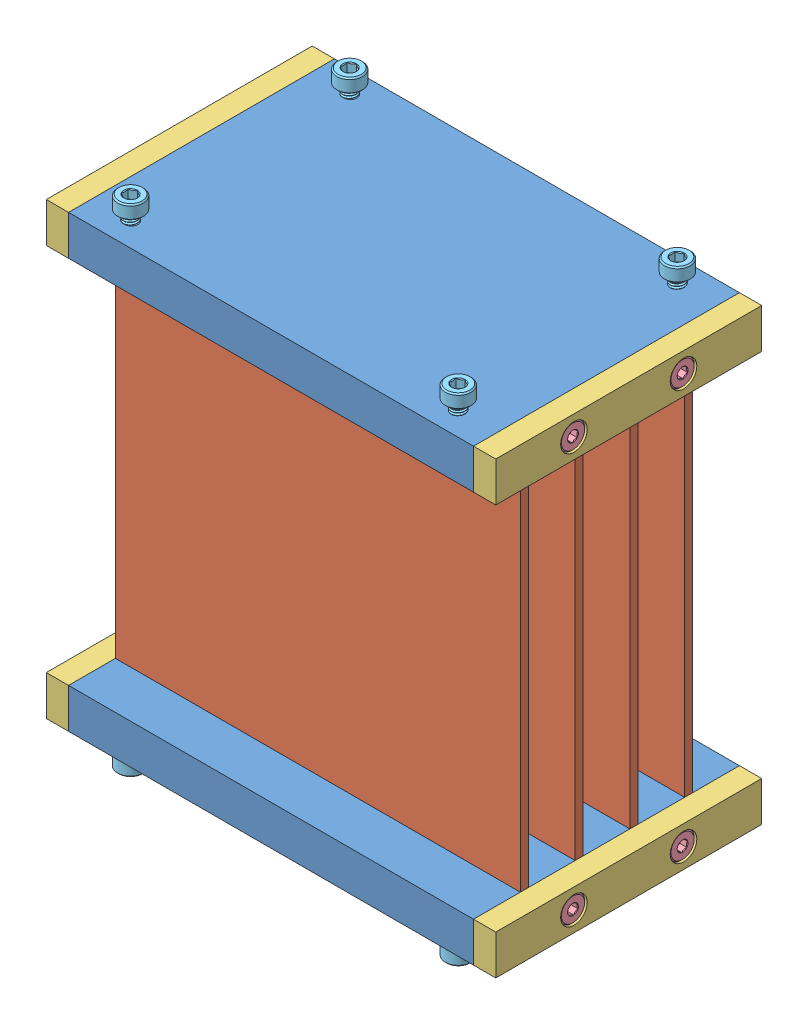
SolidWorks assembly STACK_SHELVES_ASSEMBLY, configuration Default. Lengths in mm.
Overall size (96 106.29 56.8).
26 component instances, 5 part files, 32 mates.
Components (placement in the parent):
- PCB_SHELF-1: PCB_SHELF [Default] at (-4.1696 1.9377 23.7027) x (0 1 0) z (1 0 0) size (8.5 56.8 86.5)
- FAKE_PCB-1: FAKE_PCB [Default] at (82.3304 4.4377 33.7027) x (0 1 0) z (1 0 0) size (91 1.7 86.5)
- FAKE_PCB-2: FAKE_PCB [Default] at (82.3304 4.4377 45.4027) x (0 1 0) z (1 0 0) size (91 1.7 86.5)
- FAKE_PCB-3: FAKE_PCB [Default] at (82.3304 4.4377 57.1027) x (0 1 0) z (1 0 0) size (91 1.7 86.5)
- FAKE_PCB-4: FAKE_PCB [Default] at (82.3304 4.4377 68.8027) x (0 1 0) z (1 0 0) size (91 1.7 86.5)
- PCB_SHELF-2: PCB_SHELF [Default] at (82.3304 97.9377 23.7027) x (0 -1 0) z (-1 0 0) size (8.5 56.8 86.5)
- PCB_SHELF_ENDS-1: PCB_SHELF_ENDS [Default] at (-4.1696 97.9377 80.5027) x (0 -1 0) z (-1 0 0) size (8.5 56.8 4.75)
- PCB_SHELF_ENDS-2: PCB_SHELF_ENDS [Default] at (-4.1696 10.4377 80.5027) x (0 -1 0) z (-1 0 0) size (8.5 56.8 4.75)
- PCB_SHELF_ENDS-3: PCB_SHELF_ENDS [Default] at (82.3304 89.4377 80.5027) x (0 1 0) z (1 0 0) size (8.5 56.8 4.75)
- PCB_SHELF_ENDS-4: PCB_SHELF_ENDS [Default] at (82.3304 1.9377 80.5027) x (0 1 0) z (1 0 0) size (8.5 56.8 4.75)
- M3_LP_6MM_90666A103_TYPE 316 SS LOW PROFILE SOCKET HEAD CAP SCREW-1: M3_LP_6MM_90666A103_TYPE 316 SS LOW PROFILE SOCKET HEAD CAP SCREW [90666A103] at (78.8804 6.1877 63.8027) x (0 -0.137884 0.990448) z (-1 0 0) size (5.5 5.5 8.16)
- M3_6MM_91292A111_TYPE 18-8 SS SOCKET HEAD CAP SCREW-1: M3_6MM_91292A111_TYPE 18-8 SS SOCKET HEAD CAP SCREW [91292A111] at (74.0804 93.9377 75.5027) x (0.999989 0 -0.00475) z (0 -1 0) size (5.5 5.5 9.19)
- M3_LP_6MM_90666A103_TYPE 316 SS LOW PROFILE SOCKET HEAD CAP SCREW-2: M3_LP_6MM_90666A103_TYPE 316 SS LOW PROFILE SOCKET HEAD CAP SCREW [90666A103] at (78.8804 6.1877 40.4027) x (0 -0.137884 -0.990448) z (-1 0 0) size (5.5 5.5 8.16)
- M3_LP_6MM_90666A103_TYPE 316 SS LOW PROFILE SOCKET HEAD CAP SCREW-3: M3_LP_6MM_90666A103_TYPE 316 SS LOW PROFILE SOCKET HEAD CAP SCREW [90666A103] at (78.8804 93.6877 63.8027) x (0 0.137884 0.990448) z (-1 0 0) size (5.5 5.5 8.16)
- M3_LP_6MM_90666A103_TYPE 316 SS LOW PROFILE SOCKET HEAD CAP SCREW-4: M3_LP_6MM_90666A103_TYPE 316 SS LOW PROFILE SOCKET HEAD CAP SCREW [90666A103] at (78.8804 93.6877 40.4027) x (0 0.137884 -0.990448) z (-1 0 0) size (5.5 5.5 8.16)
- M3_LP_6MM_90666A103_TYPE 316 SS LOW PROFILE SOCKET HEAD CAP SCREW-5: M3_LP_6MM_90666A103_TYPE 316 SS LOW PROFILE SOCKET HEAD CAP SCREW [90666A103] at (-0.7196 6.1877 63.8027) x (0 -0.137884 0.990448) z (1 0 0) size (5.5 5.5 8.16)
- M3_LP_6MM_90666A103_TYPE 316 SS LOW PROFILE SOCKET HEAD CAP SCREW-6: M3_LP_6MM_90666A103_TYPE 316 SS LOW PROFILE SOCKET HEAD CAP SCREW [90666A103] at (-0.7196 6.1877 40.4027) x (0 -0.137884 -0.990448) z (1 0 0) size (5.5 5.5 8.16)
- M3_LP_6MM_90666A103_TYPE 316 SS LOW PROFILE SOCKET HEAD CAP SCREW-7: M3_LP_6MM_90666A103_TYPE 316 SS LOW PROFILE SOCKET HEAD CAP SCREW [90666A103] at (-0.7196 93.6877 63.8027) x (0 0.137884 0.990448) z (1 0 0) size (5.5 5.5 8.16)
- M3_LP_6MM_90666A103_TYPE 316 SS LOW PROFILE SOCKET HEAD CAP SCREW-8: M3_LP_6MM_90666A103_TYPE 316 SS LOW PROFILE SOCKET HEAD CAP SCREW [90666A103] at (-0.7196 93.6877 40.4027) x (0 0.137884 -0.990448) z (1 0 0) size (5.5 5.5 8.16)
- M3_6MM_91292A111_TYPE 18-8 SS SOCKET HEAD CAP SCREW-2: M3_6MM_91292A111_TYPE 18-8 SS SOCKET HEAD CAP SCREW [91292A111] at (74.0804 93.9377 28.7027) x (0.999989 0 0.00475) z (0 -1 0) size (5.5 5.5 9.19)
- M3_6MM_91292A111_TYPE 18-8 SS SOCKET HEAD CAP SCREW-3: M3_6MM_91292A111_TYPE 18-8 SS SOCKET HEAD CAP SCREW [91292A111] at (4.0804 93.9377 75.5027) x (-0.999989 0 -0.00475) z (0 -1 0) size (5.5 5.5 9.19)
- M3_6MM_91292A111_TYPE 18-8 SS SOCKET HEAD CAP SCREW-4: M3_6MM_91292A111_TYPE 18-8 SS SOCKET HEAD CAP SCREW [91292A111] at (4.0804 93.9377 28.7027) x (-0.999989 0 0.00475) z (0 -1 0) size (5.5 5.5 9.19)
- M3_6MM_91292A111_TYPE 18-8 SS SOCKET HEAD CAP SCREW-5: M3_6MM_91292A111_TYPE 18-8 SS SOCKET HEAD CAP SCREW [91292A111] at (74.0804 5.9377 75.5027) x (0.999989 0 -0.00475) z (0 1 0) size (5.5 5.5 9.19)
- M3_6MM_91292A111_TYPE 18-8 SS SOCKET HEAD CAP SCREW-6: M3_6MM_91292A111_TYPE 18-8 SS SOCKET HEAD CAP SCREW [91292A111] at (74.0804 5.9377 28.7027) x (0.999989 0 0.00475) z (0 1 0) size (5.5 5.5 9.19)
- M3_6MM_91292A111_TYPE 18-8 SS SOCKET HEAD CAP SCREW-7: M3_6MM_91292A111_TYPE 18-8 SS SOCKET HEAD CAP SCREW [91292A111] at (4.0804 5.9377 75.5027) x (-0.999989 0 -0.00475) z (0 1 0) size (5.5 5.5 9.19)
- M3_6MM_91292A111_TYPE 18-8 SS SOCKET HEAD CAP SCREW-8: M3_6MM_91292A111_TYPE 18-8 SS SOCKET HEAD CAP SCREW [91292A111] at (4.0804 5.9377 28.7027) x (-0.999989 0 0.00475) z (0 1 0) size (5.5 5.5 9.19)
Mates (geometry in assembly coordinates):
- Coincident10: coincident anti-aligned: plane of PCB_SHELF-1 through (82.3304 4.4377 35.4027) normal (0 1 0); plane of FAKE_PCB-1 through (82.3304 4.4377 35.4027) normal (0 -1 0)
- Coincident11: coincident anti-aligned: plane of PCB_SHELF-1 through (82.3304 4.4377 33.7027) normal (0 0 1); plane of FAKE_PCB-1 through (82.3304 4.4377 33.7027) normal (0 0 -1)
- Coincident12: coincident aligned: plane of PCB_SHELF-1 through (82.3304 1.9377 23.7027) normal (1 0 0); plane of FAKE_PCB-1 through (82.3304 95.4377 35.4027) normal (1 0 0)
- Coincident13: coincident anti-aligned: plane of PCB_SHELF-1 through (82.3304 4.4377 47.1027) normal (0 1 0); plane of FAKE_PCB-2 through (82.3304 4.4377 47.1027) normal (0 -1 0)
- Coincident14: coincident anti-aligned: plane of PCB_SHELF-1 through (82.3304 4.4377 45.4027) normal (0 0 1); plane of FAKE_PCB-2 through (82.3304 4.4377 45.4027) normal (0 0 -1)
- Coincident15: coincident aligned: plane of PCB_SHELF-1 through (-4.1696 1.9377 23.7027) normal (-1 0 0); plane of FAKE_PCB-2 through (-4.1696 4.4377 47.1027) normal (-1 0 0)
- Coincident16: coincident anti-aligned: plane of PCB_SHELF-1 through (82.3304 4.4377 58.8027) normal (0 1 0); plane of FAKE_PCB-3 through (82.3304 4.4377 58.8027) normal (0 -1 0)
- Coincident17: coincident anti-aligned: plane of PCB_SHELF-1 through (82.3304 4.4377 57.1027) normal (0 0 1); plane of FAKE_PCB-3 through (82.3304 4.4377 57.1027) normal (0 0 -1)
- Coincident18: coincident aligned: plane of PCB_SHELF-1 through (-4.1696 1.9377 23.7027) normal (-1 0 0); plane of FAKE_PCB-3 through (-4.1696 4.4377 58.8027) normal (-1 0 0)
- Coincident19: coincident anti-aligned: plane of PCB_SHELF-1 through (82.3304 4.4377 70.5027) normal (0 1 0); plane of FAKE_PCB-4 through (82.3304 4.4377 70.5027) normal (0 -1 0)
- Coincident20: coincident anti-aligned: plane of PCB_SHELF-1 through (82.3304 4.4377 68.8027) normal (0 0 1); plane of FAKE_PCB-4 through (82.3304 4.4377 68.8027) normal (0 0 -1)
- Coincident21: coincident aligned: plane of PCB_SHELF-1 through (-4.1696 1.9377 23.7027) normal (-1 0 0); plane of FAKE_PCB-4 through (-4.1696 4.4377 70.5027) normal (-1 0 0)
- Coincident22: coincident anti-aligned: plane of FAKE_PCB-4 through (-4.1696 95.4377 70.5027) normal (0 1 0); plane of PCB_SHELF-2 through (-4.1696 95.4377 70.5027) normal (0 -1 0)
- Coincident23: coincident aligned: plane of FAKE_PCB-4 through (82.3304 95.4377 70.5027) normal (1 0 0); plane of PCB_SHELF-2 through (82.3304 97.9377 23.7027) normal (1 0 0)
- Coincident24: coincident aligned: plane of FAKE_PCB-1 through (82.3304 95.4377 35.4027) normal (1 0 0); plane of PCB_SHELF-2 through (82.3304 97.9377 23.7027) normal (1 0 0)
- Coincident25: coincident anti-aligned: plane of FAKE_PCB-1 through (82.3304 4.4377 35.4027) normal (0 0 1); plane of PCB_SHELF-2 through (-4.1696 89.4377 35.4027) normal (0 0 -1)
- Concentric1: concentric aligned: cylinder of PCB_SHELF-1 through (82.3304 6.1877 63.8027) axis (1 0 0) radius 1.25; cylinder of PCB_SHELF_ENDS-4 through (87.0804 6.1877 63.8027) axis (1 0 0) radius 1.5
- Coincident26: coincident anti-aligned: plane of PCB_SHELF-1 through (82.3304 1.9377 23.7027) normal (1 0 0); plane of PCB_SHELF_ENDS-4 through (82.3304 1.9377 80.5027) normal (-1 0 0)
- Concentric2: concentric aligned: cylinder of PCB_SHELF-1 through (82.3304 6.1877 40.4027) axis (1 0 0) radius 1.25; cylinder of PCB_SHELF_ENDS-4 through (87.0804 6.1877 40.4027) axis (1 0 0) radius 1.5
- Coincident27: coincident anti-aligned: plane of PCB_SHELF-2 through (82.3304 97.9377 23.7027) normal (1 0 0); plane of PCB_SHELF_ENDS-3 through (82.3304 89.4377 80.5027) normal (-1 0 0)
- Concentric3: concentric aligned: cylinder of PCB_SHELF-2 through (82.3304 93.6877 63.8027) axis (1 0 0) radius 1.25; cylinder of PCB_SHELF_ENDS-3 through (87.0804 93.6877 63.8027) axis (1 0 0) radius 1.5
- Concentric4: concentric aligned: cylinder of PCB_SHELF-2 through (82.3304 93.6877 40.4027) axis (1 0 0) radius 1.25; cylinder of PCB_SHELF_ENDS-3 through (87.0804 93.6877 40.4027) axis (1 0 0) radius 1.5
- Coincident28: coincident anti-aligned: plane of PCB_SHELF-1 through (-4.1696 1.9377 23.7027) normal (-1 0 0); plane of PCB_SHELF_ENDS-2 through (-4.1696 10.4377 80.5027) normal (1 0 0)
- Concentric5: concentric aligned: cylinder of PCB_SHELF-1 through (-4.1696 6.1877 63.8027) axis (-1 0 0) radius 1.25; cylinder of PCB_SHELF_ENDS-2 through (-8.9196 6.1877 63.8027) axis (-1 0 0) radius 1.5
- Concentric6: concentric aligned: cylinder of PCB_SHELF-1 through (-4.1696 6.1877 40.4027) axis (-1 0 0) radius 1.25; cylinder of PCB_SHELF_ENDS-2 through (-8.9196 6.1877 40.4027) axis (-1 0 0) radius 1.5
- Coincident29: coincident anti-aligned: plane of PCB_SHELF-2 through (-4.1696 97.9377 23.7027) normal (-1 0 0); plane of PCB_SHELF_ENDS-1 through (-4.1696 97.9377 80.5027) normal (1 0 0)
- Concentric7: concentric aligned: cylinder of PCB_SHELF-2 through (-4.1696 93.6877 63.8027) axis (-1 0 0) radius 1.25; cylinder of PCB_SHELF_ENDS-1 through (-8.9196 93.6877 63.8027) axis (-1 0 0) radius 1.5
- Concentric8: concentric aligned: cylinder of PCB_SHELF-2 through (-4.1696 93.6877 40.4027) axis (-1 0 0) radius 1.25; cylinder of PCB_SHELF_ENDS-1 through (-8.9196 93.6877 40.4027) axis (-1 0 0) radius 1.5
- Concentric9: concentric anti-aligned: circle of PCB_SHELF_ENDS-4; circle of M3_LP_6MM_90666A103_TYPE 316 SS LOW PROFILE SOCKET HEAD CAP SCREW-1
- Coincident31: coincident anti-aligned: plane of PCB_SHELF_ENDS-4 through (84.8804 6.1877 63.8027) normal (1 0 0); plane of M3_LP_6MM_90666A103_TYPE 316 SS LOW PROFILE SOCKET HEAD CAP SCREW-1 through (84.8804 6.1877 63.8027) normal (-1 0 0)
- Concentric10: concentric anti-aligned: circle of PCB_SHELF-2; circle of M3_6MM_91292A111_TYPE 18-8 SS SOCKET HEAD CAP SCREW-1
- Distance1: distance = 2 mm anti-aligned: plane of PCB_SHELF-2 through (-4.1696 97.9377 23.7027) normal (0 1 0); plane of M3_6MM_91292A111_TYPE 18-8 SS SOCKET HEAD CAP SCREW-1 through (74.0804 99.9377 75.5027) normal (0 -1 0)
